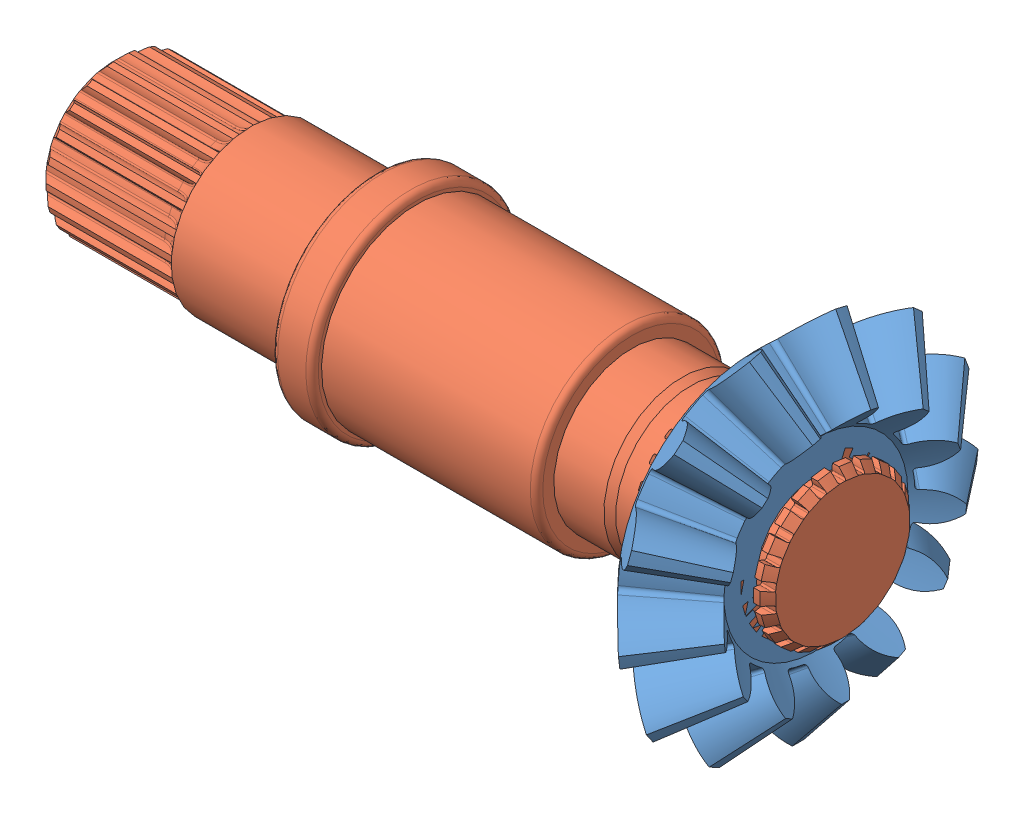
SolidWorks assembly Assem1, configuration Default. Lengths in mm.
Overall size (117.36 57.99 58.17).
2 component instances, 2 part files, 2 mates.
Components (placement in the parent):
- Miter Gear-1: Miter Gear [Default] at (-8.7062 30.0142 58.3845) size (19.79 57.99 58.17)
- Gear_Rod-1: Gear_Rod [Default] at (-111.0762 30.0142 58.3845) x (1 0 0) z (0 -0.541726 0.840555) size (116.5 33.5 33.5)
Mates (geometry in assembly coordinates):
- Concentric2: concentric: circle of Miter Gear-1; cylinder of Gear_Rod-1 through (-109.2575 30.0142 58.3845) axis (-1 0 0) radius 15.25
- Coincident1: coincident anti-aligned: plane of Miter Gear-1; plane of Gear_Rod-1 through (1.1501 37.9995 63.5309) normal (1 0 0)
